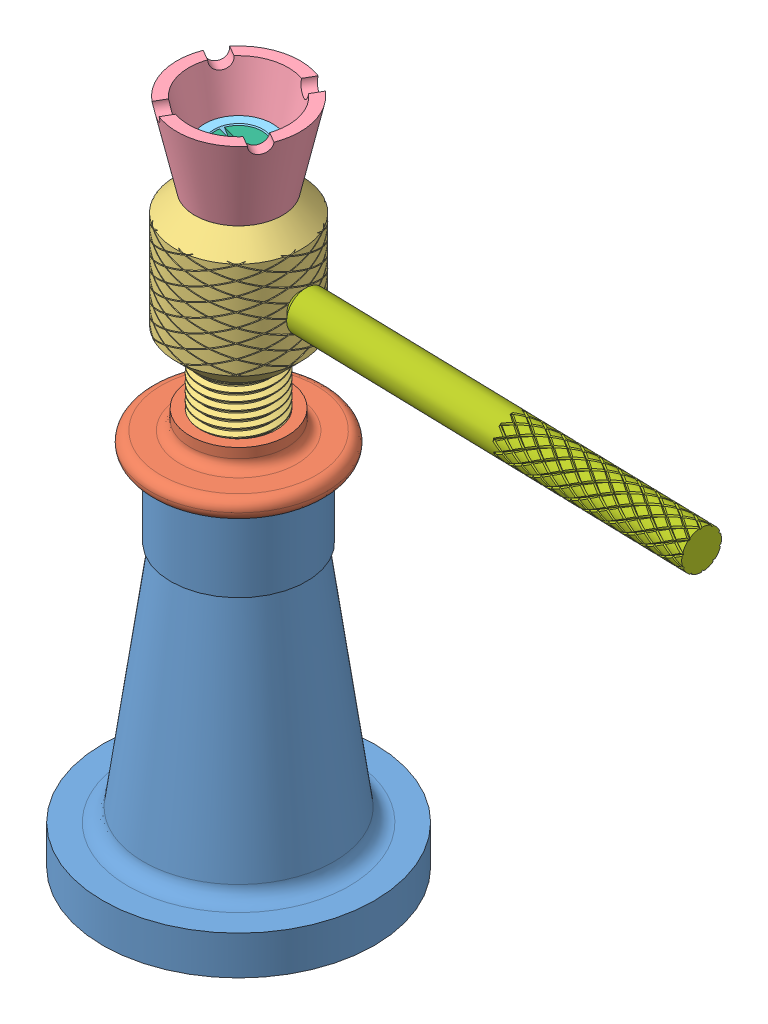
SolidWorks assembly Assem1, configuration Default. Lengths in mm.
Overall size (315.35 344.48 140).
7 component instances, 7 part files, 15 mates.
Components (placement in the parent):
- Part1-1: Part1 [Default] at origin size (140 185 140)
- Part2-1: Part2 [Default] at (0 160 0) size (90 46.51 90)
- Part3-1: Part3 [Default] at (0 75.1892 0) x (0.025256 0 -0.999681) z (0.999681 0 0.025256) size (65.38 240 65.37)
- Part4-2: Part4 [Default] at (0 302.1892 0) x (0.500834 0 -0.865543) z (0.865543 0 0.500834) size (63.3 42.29 63.3)
- Part5-1: Part5 [Default] at (0 315.1892 0) x (0.757806 0 0.65248) z (-0.65248 0 0.757806) size (35 8 35)
- Part6-1: Part6 [Default] at (0 292.6892 0) x (-0.254676 0 0.967026) z (-0.967026 0 -0.254676) size (24 30 23.92)
- Part7-3: Part7 [Default] at (-30.0491 267.1892 -0.7591) x (0.999681 0 0.025256) z (0.023101 -0.404135 -0.914407) size (275.15 20.14 20.13)
Mates (geometry in assembly coordinates):
- Coincident1: coincident aligned: plane of Part1-1 through (0 0 0) normal (0 0 1)
- Coincident2: coincident aligned: plane of Part1-1 through (0 0 0) normal (0 1 0)
- Coincident3: coincident aligned: plane of Part1-1 through (0 0 0) normal (1 0 0)
- Concentric1: concentric aligned: cylinder of Part1-1 through (0 0 0) axis (0 -1 0) radius 25; cylinder of Part2-1 through (0 160 0) axis (0 -1 0) radius 25
- Coincident4: coincident anti-aligned: plane of Part1-1 through (35 185 0) normal (0 1 0); plane of Part2-1 through (45 185 0) normal (0 -1 0)
- Screw1: screw = 10 mm anti-aligned: cylinder of Part2-1 through (0 160 0) axis (0 -1 0) radius 19.5; cylinder of Part3-1 through (0 315.1892 0) axis (0 1 0) radius 19.5
- Concentric2: concentric anti-aligned: cylinder of Part3-1 through (0 315.1892 0) axis (0 1 0) radius 11; cylinder of Part4-2 through (0 302.1892 0) axis (0 -1 0) radius 11
- Coincident5: coincident anti-aligned: plane of Part3-1 through (0.8208 302.1892 -32.4896) normal (0 1 0); plane of Part4-2 through (5.9503 302.1892 -10.2834) normal (0 -1 0)
- Concentric3: concentric anti-aligned: cylinder of Part3-1 through (0 315.1892 0) axis (0 1 0) radius 11; cylinder of Part5-1 through (0 315.1892 0) axis (0 -1 0) radius 17.5
- Coincident6: coincident anti-aligned: plane of Part3-1 through (0.2778 315.1892 -10.9965) normal (0 1 0); plane of Part5-1 through (5.4941 315.1892 4.7305) normal (0 -1 0)
- Concentric4: concentric anti-aligned: cylinder of Part5-1 through (0 315.1892 0) axis (0 -1 0) radius 7.25; circle of Part6-1
- Coincident7: coincident aligned: cone of Part5-1 through (0 323.1892 0) axis (0 -1 0); cone of Part6-1 through (0 316.6892 0) axis (0 -1 0)
- Concentric12: concentric aligned: cylinder of Part3-1 through (-40.9869 267.1892 -1.0355) axis (0.999681 0 0.025256) radius 6; cylinder of Part7-3 through (244.8632 267.1892 6.1861) axis (0.999681 0 0.025256) radius 6
- Concentric13: concentric aligned: cylinder of Part3-1 through (-40.9869 267.1892 -1.0355) axis (0.999681 0 0.025256) radius 6; cylinder of Part7-3 through (244.8632 267.1892 6.1861) axis (0.999681 0 0.025256) radius 6
- Tangent4: tangent: curve of Part3-1; circle of Part7-3
